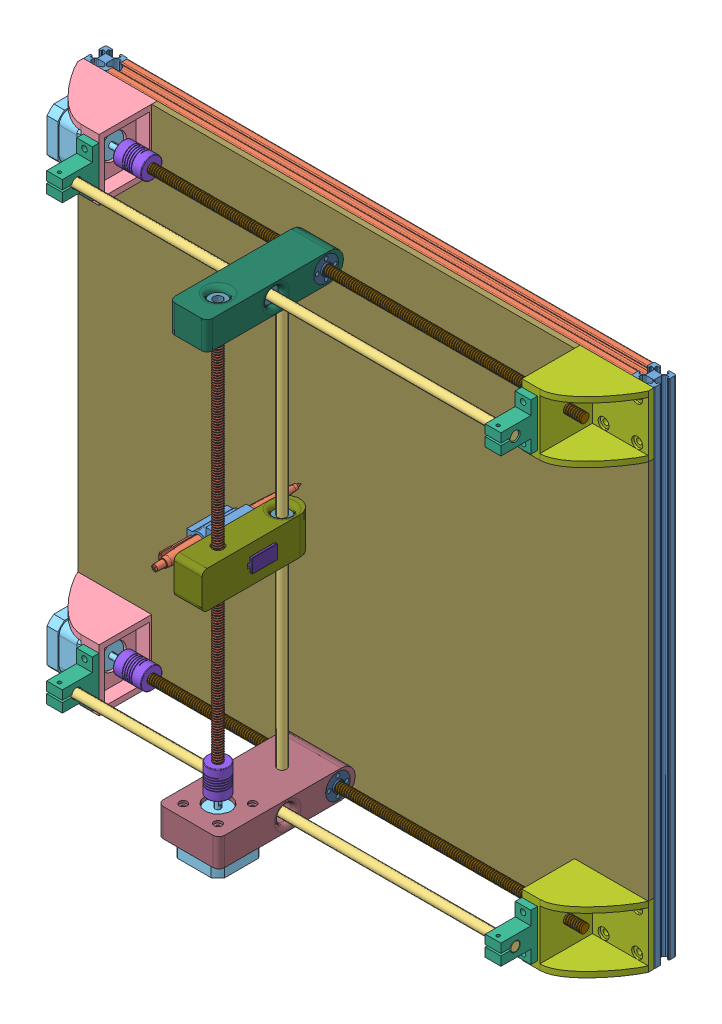
SolidWorks assembly Assem1, configuration Default. Lengths in mm.
Overall size (510 601.35 155.57).
39 component instances, 20 part files, 97 mates.
Components (placement in the parent):
- Profile20X20X450-1: Profile20X20X450 [Default] at (128.2703 40.515 345.5202) size (20 450 20)
- Profile20X20X470-1: Profile20X20X470 [Default] at (118.2703 50.515 345.5202) x (0 1 0) z (0 0 1) size (20 470 20)
- Profile20X20X450-2: Profile20X20X450 [Default] at (-361.7297 40.515 345.5202) size (20 450 20)
- Profile20X20X470-2: Profile20X20X470 [Default] at (118.2703 480.515 345.5202) x (0 0 -1) z (0 1 0) size (20 470 20)
- Rod405-1: Rod405 [Default] at (85.2703 463.015 427.5202) x (0 -0.389511 0.921022) z (0 -0.921022 -0.389511) size (8 405 8)
- Y Motor Mount-1: Y Motor Mount [Default] at (-346.7297 463.015 355.5202) x (0 -1 0) z (0 0 1) size (55 66 52)
- NEMA17-1: NEMA17 [Default] at (-321.7297 463.015 382.5202) x (-1 0 0) z (0 0 1) size (54.3 42.3 42.3)
- Rod Support-1: Rod Support [Default] at (-319.7297 463.015 410.5202) x (0 1 0) z (1 0 0) size (42 32.8 14)
- Y Mount-1: Y Mount [Default] at (113.2703 463.015 355.5202) x (0 1 0) z (0 0 1) size (55 66 52)
- Rod Support-2: Rod Support [Default] at (72.2703 463.015 410.5202) x (0 1 0) z (1 0 0) size (42 32.8 14)
- Coupling-1: Coupling [Default] at (-308.7297 463.015 382.5202) x (0 -0.956542 -0.291595) z (0 -0.291595 0.956542) size (19.01 25 19.98)
- Lead Screw 405-1: Lead Screw 405 [Default] at (-301.7297 463.015 382.5202) x (0 0.596667 -0.802489) z (0 -0.802489 -0.596667) size (8.47 411.14 9.26)
- NEMA17-2: NEMA17 [Default] at (-321.7297 68.015 382.5202) x (-1 0 0) z (0 0 1) size (54.3 42.3 42.3)
- Y Motor Mount-2: Y Motor Mount [Default] at (-346.7297 68.015 355.5202) x (0 -1 0) z (0 0 1) size (55 66 52)
- Rod405-2: Rod405 [Default] at (86.2703 68.015 427.5202) x (0 1 0) z (0 0 1) size (8 405 8)
- Rod Support-3: Rod Support [Default] at (-305.7297 68.015 410.5202) x (0 -1 0) z (-1 0 0) size (42 32.8 14)
- Y Mount-2: Y Mount [Default] at (113.2703 68.015 355.5202) x (0 1 0) z (0 0 1) size (55 66 52)
- Rod Support-4: Rod Support [Default] at (72.2703 68.015 410.5202) x (0 1 0) z (1 0 0) size (42 32.8 14)
- Coupling-2: Coupling [Default] at (-308.7297 68.015 382.5202) x (0 -0.905924 -0.42344) z (0 -0.42344 0.905924) size (19.01 25 19.98)
- Lead Screw 405-2: Lead Screw 405 [Default] at (-301.7297 68.015 382.5202) x (0 0.781118 -0.624384) z (0 -0.624384 -0.781118) size (8.47 411.14 9.26)
- Lead Screw Nut-1: Lead Screw Nut [Default] at (-117.1715 68.015 382.5202) x (0 -1 0) z (0 0 -1) size (22 16.61 22)
- Lead Screw Nut-2: Lead Screw Nut [Default] at (-127.6715 463.015 382.5202) x (0 -1 0) z (0 0 -1) size (22 16.61 22)
- Lead Screw 355-2: Lead Screw 355 [Default] at (-144.6715 95.515 462.2702) x (0.982445 0 -0.186554) z (0.186554 0 0.982445) size (8.47 360.68 9.26)
- Bottom Board-1: Bottom Board [Default] at (-116.7297 265.515 355.5202) x (0 1 0) z (1 0 0) size (601.35 5 510)
- X Motor Mount-1: X Motor Mount [Default] at (-144.6715 80.515 428.0202) x (1 0 0) z (0 -1 0) size (55 122 25)
- Rod Bearing-1: Rod Bearing [Default] at (-156.6715 68.015 427.5202) x (0 -1 0) z (0 0 1) size (15 24 15)
- NEMA17-3: NEMA17 [Default] at (-144.6715 75.515 462.2702) x (0 -1 0) z (0 0 1) size (54.3 42.3 42.3)
- Coupling-3: Coupling [Default] at (-144.6715 88.515 462.2702) x (-0.731937 0 -0.681372) z (0.681372 0 -0.731937) size (19.01 25 19.98)
- Rod405-3: Rod405 [Default] at (-144.6715 62.515 405.0202) x (0.332064 0 -0.943257) z (0.943257 0 0.332064) size (8 405 8)
- X Mount-1: X Mount [Default] at (-144.6715 450.515 428.0202) x (-1 0 0) z (0 1 0) size (34 122 25)
- Rod Bearing-2: Rod Bearing [Default] at (-157.1715 463.015 427.5202) x (0 -1 0) z (0 0 1) size (15 24 15)
- Rod Bearing-3: Rod Bearing [Default] at (-144.6715 471.015 462.2702) x (-1 0 0) z (0 0 1) size (15 24 15)
- Laser Mount-1: Laser Mount [Default] at (-157.1715 263.4641 439.0202) x (0 1 0) z (1 0 0) size (33 100 27)
- Rod Bearing-4: Rod Bearing [Default] at (-144.6715 275.4641 405.0202) x (0.034876 0 0.999392) z (0.999392 0 -0.034876) size (15 24 15)
- Lead Screw Nut-3: Lead Screw Nut [Default] at (-144.6715 246.9641 462.2702) x (-1 0 0) z (0 0 -1) size (22 16.61 22)
- SG90-1: SG90 [По умолчанию] at (-130.1715 263.4641 434.7702) x (0 0 1) z (0 -1 0) size (32.5 30.1 12.68)
- Servo Arm-1: Servo Arm [Default] at (-161.9715 263.4641 429.5202) x (0 -0.999945 -0.010487) z (0 -0.010487 0.999945) size (19.64 3.7 7)
- Laser holder-1: Laser holder [Default] at (-157.1715 263.2641 433.5202) x (0 -1 0) z (0 0 -1) size (30 26.04 36)
- Pen-1: Pen [Default] at (-172.4961 263.2641 364.5065) x (0.849805 -0.527097 0) z (-0.527097 -0.849805 0) size (12.47 130.57 10.33)
Mates (geometry in assembly coordinates):
- Coincident1: coincident aligned: plane of Profile20X20X450-1 through (119.7703 490.515 355.5202) normal (0 0 1); plane of Profile20X20X450-2 through (-370.2297 490.515 355.5202) normal (0 0 1)
- Coincident2: coincident aligned: plane of Profile20X20X450-1 through (122.8703 40.515 348.2686) normal (0 -1 0); plane of Profile20X20X450-2 through (-367.1297 40.515 348.2686) normal (0 -1 0)
- Coincident3: coincident aligned: plane of Profile20X20X450-1 through (136.7703 490.515 355.5202) normal (0 0 1); plane of Profile20X20X470-1 through (-351.7297 59.015 355.5202) normal (0 0 1)
- Coincident4: coincident anti-aligned: plane of Profile20X20X450-1 through (118.2703 490.515 354.0202) normal (-1 0 0); plane of Profile20X20X470-1 through (118.2703 45.115 348.2686) normal (1 0 0)
- Coincident5: coincident aligned: plane of Profile20X20X450-1 through (122.8703 40.515 348.2686) normal (0 -1 0); plane of Profile20X20X470-1 through (-351.7297 40.515 354.0202) normal (0 -1 0)
- Coincident6: coincident anti-aligned: plane of Profile20X20X470-1 through (-351.7297 45.115 348.2686) normal (-1 0 0); plane of Profile20X20X450-2 through (-351.7297 490.515 349.9202) normal (1 0 0)
- Coincident7: coincident aligned: plane of Profile20X20X450-1 through (119.7703 490.515 355.5202) normal (0 0 1); plane of Profile20X20X470-2 through (-351.7297 489.015 355.5202) normal (0 0 1)
- Coincident8: coincident anti-aligned: plane of Profile20X20X450-1 through (118.2703 490.515 337.0202) normal (-1 0 0); plane of Profile20X20X470-2 through (118.2703 483.2634 350.9202) normal (1 0 0)
- Coincident9: coincident aligned: plane of Profile20X20X450-1 through (122.8703 490.515 348.2686) normal (0 1 0); plane of Profile20X20X470-2 through (-351.7297 490.515 337.0202) normal (0 1 0)
- Coincident10: coincident anti-aligned: plane of Profile20X20X470-2 through (-351.7297 489.015 355.5202) normal (0 0 1); plane of Y Motor Mount-1 through (-346.7297 463.015 355.5202) normal (0 0 -1)
- Coincident11: coincident aligned: plane of Profile20X20X450-2 through (-367.1297 490.515 348.2686) normal (0 1 0); plane of Y Motor Mount-1 through (-321.7297 490.515 360.5202) normal (0 1 0)
- Coincident12: coincident aligned: plane of Profile20X20X450-2 through (-371.7297 490.515 354.0202) normal (-1 0 0); plane of Y Motor Mount-1 through (-371.7297 490.515 360.5202) normal (-1 0 0)
- Concentric1: concentric aligned: cylinder of Y Motor Mount-1 through (-305.7297 463.015 382.5202) axis (-1 0 0) radius 11.5; cylinder of NEMA17-1 through (-321.2297 463.015 382.5202) axis (-1 0 0) radius 11
- Coincident13: coincident anti-aligned: plane of Y Motor Mount-1 through (-321.7297 463.015 355.5202) normal (-1 0 0); plane of NEMA17-1 through (-321.7297 463.015 382.5202) normal (1 0 0)
- Parallel1: parallel aligned: plane of Y Motor Mount-1 through (-346.7297 463.015 360.5202) normal (0 0 1); plane of NEMA17-1 through (-325.5547 463.015 403.6702) normal (0 0 1)
- Concentric2: concentric aligned: cylinder of Y Motor Mount-1 through (-312.7297 479.015 402.5202) axis (0 0 1) radius 2.5; cylinder of Rod Support-1 through (-312.7297 479.015 407.5192) axis (0 0 1) radius 2.5
- Coincident15: coincident anti-aligned: plane of Y Motor Mount-1 through (-305.7297 490.515 407.5202) normal (0 0 1); plane of Rod Support-1 through (-305.7297 442.015 407.5202) normal (0 0 -1)
- Coincident16: coincident aligned: plane of Y Motor Mount-1 through (-305.7297 463.015 355.5202) normal (1 0 0); plane of Rod Support-1 through (-305.7297 463.015 427.5202) normal (1 0 0)
- Concentric5: concentric anti-aligned: cylinder of Rod405-1 through (-319.7297 463.015 427.5202) axis (1 0 0) radius 4; cylinder of Rod Support-1 through (-305.7297 463.015 427.5202) axis (-1 0 0) radius 4.5
- Coincident17: coincident aligned: plane of Rod405-1 through (-319.7297 463.015 427.5202) normal (-1 0 0); plane of Rod Support-1 through (-319.7297 463.015 427.5202) normal (-1 0 0)
- Coincident18: coincident aligned: plane of Profile20X20X450-1 through (138.2703 490.515 349.9202) normal (1 0 0); plane of Y Mount-1 through (138.2703 435.515 360.5202) normal (1 0 0)
- Coincident19: coincident anti-aligned: plane of Profile20X20X450-1 through (119.7703 490.515 355.5202) normal (0 0 1); plane of Y Mount-1 through (113.2703 463.015 355.5202) normal (0 0 -1)
- Coincident20: coincident aligned: plane of Profile20X20X450-1 through (122.8703 490.515 348.2686) normal (0 1 0); plane of Y Mount-1 through (88.2703 490.515 360.5202) normal (0 1 0)
- Concentric6: concentric anti-aligned: cylinder of Rod405-1 through (-319.7297 463.015 427.5202) axis (1 0 0) radius 4; cylinder of Rod Support-2 through (86.2703 463.015 427.5202) axis (-1 0 0) radius 4.5
- Concentric8: concentric aligned: cylinder of Y Mount-1 through (79.2703 447.015 402.5202) axis (0 0 1) radius 2.5; cylinder of Rod Support-2 through (79.2703 447.015 407.5192) axis (0 0 1) radius 2.5
- Concentric9: concentric aligned: cylinder of NEMA17-1 through (-317.4797 463.015 382.5202) axis (-1 0 0) radius 2.5; cylinder of Coupling-1 through (-283.7297 463.015 382.5202) axis (-1 0 0) radius 2.5
- Coincident21: coincident aligned: plane of NEMA17-1 through (-301.7297 462.015 382.5202) normal (1 0 0); plane of Coupling-1 through (-301.7297 463.015 382.5202) normal (1 0 0)
- Concentric10: concentric anti-aligned: cylinder of Coupling-1 through (-301.7297 463.015 382.5202) axis (1 0 0) radius 4; cylinder of Lead Screw 405-1 through (103.2703 463.015 382.5202) axis (-1 0 0) radius 4
- Coincident22: coincident anti-aligned: plane of Coupling-1 through (-301.7297 463.015 382.5202) normal (1 0 0); plane of Lead Screw 405-1 through (-301.7297 463.015 382.5202) normal (-1 0 0)
- Coincident23: coincident aligned: plane of Profile20X20X450-2 through (-367.1297 40.515 348.2686) normal (0 -1 0); plane of Y Motor Mount-2 through (-321.7297 40.515 360.5202) normal (0 -1 0)
- Coincident24: coincident anti-aligned: plane of Profile20X20X450-2 through (-353.2297 490.515 355.5202) normal (0 0 1); plane of Y Motor Mount-2 through (-346.7297 68.015 355.5202) normal (0 0 -1)
- Coincident25: coincident aligned: plane of Profile20X20X450-2 through (-371.7297 490.515 337.0202) normal (-1 0 0); plane of Y Motor Mount-2 through (-371.7297 95.515 360.5202) normal (-1 0 0)
- Concentric12: concentric aligned: cylinder of NEMA17-2 through (-317.4797 68.015 382.5202) axis (-1 0 0) radius 2.5; cylinder of Y Motor Mount-2 through (-305.7297 68.015 382.5202) axis (-1 0 0) radius 11.5
- Coincident26: coincident anti-aligned: plane of NEMA17-2 through (-321.7297 68.015 382.5202) normal (1 0 0); plane of Y Motor Mount-2 through (-321.7297 68.015 355.5202) normal (-1 0 0)
- Parallel4: parallel aligned: plane of NEMA17-2 through (-325.5547 68.015 403.6702) normal (0 0 1); plane of Y Motor Mount-2 through (-305.7297 95.515 407.5202) normal (0 0 1)
- Concentric13: concentric aligned: cylinder of Y Motor Mount-2 through (-312.7297 84.015 402.5202) axis (0 0 1) radius 2.5; cylinder of Rod Support-3 through (-312.7297 84.015 407.5192) axis (0 0 1) radius 2.5
- Coincident28: coincident anti-aligned: plane of Y Motor Mount-2 through (-305.7297 95.515 407.5202) normal (0 0 1); plane of Rod Support-3 through (-319.7297 89.015 407.5202) normal (0 0 -1)
- Concentric14: concentric aligned: cylinder of Y Motor Mount-2 through (-312.7297 52.015 402.5202) axis (0 0 1) radius 2.5; cylinder of Rod Support-3 through (-312.7297 52.015 407.5192) axis (0 0 1) radius 2.5
- Coincident29: coincident aligned: plane of Profile20X20X450-1 through (122.8703 40.515 348.2686) normal (0 -1 0); plane of Y Mount-2 through (88.2703 40.515 360.5202) normal (0 -1 0)
- Coincident30: coincident aligned: plane of Profile20X20X450-1 through (138.2703 490.515 349.9202) normal (1 0 0); plane of Y Mount-2 through (138.2703 40.515 360.5202) normal (1 0 0)
- Coincident31: coincident anti-aligned: plane of Profile20X20X450-1 through (119.7703 490.515 355.5202) normal (0 0 1); plane of Y Mount-2 through (113.2703 68.015 355.5202) normal (0 0 -1)
- Concentric15: concentric aligned: cylinder of Y Mount-2 through (79.2703 52.015 402.5202) axis (0 0 1) radius 2.5; cylinder of Rod Support-4 through (79.2703 52.015 407.5192) axis (0 0 1) radius 2.5
- Concentric16: concentric aligned: cylinder of Y Mount-2 through (79.2703 84.015 402.5202) axis (0 0 1) radius 2.5; cylinder of Rod Support-4 through (79.2703 84.015 407.5192) axis (0 0 1) radius 2.5
- Coincident32: coincident anti-aligned: plane of Y Mount-2 through (72.2703 40.515 407.5202) normal (0 0 1); plane of Rod Support-4 through (86.2703 47.015 407.5202) normal (0 0 -1)
- Concentric17: concentric aligned: cylinder of Rod405-2 through (-318.7297 68.015 427.5202) axis (1 0 0) radius 4; cylinder of Rod Support-3 through (-319.7297 68.015 427.5202) axis (1 0 0) radius 4.5
- Coincident33: coincident aligned: plane of Rod405-2 through (86.2703 68.015 427.5202) normal (1 0 0); plane of Rod Support-4 through (86.2703 68.015 427.5202) normal (1 0 0)
- Concentric19: concentric aligned: cylinder of NEMA17-2 through (-317.4797 68.015 382.5202) axis (-1 0 0) radius 2.5; cylinder of Coupling-2 through (-283.7297 68.015 382.5202) axis (-1 0 0) radius 2.5
- Coincident34: coincident aligned: plane of NEMA17-2 through (-301.7297 67.015 382.5202) normal (1 0 0); plane of Coupling-2 through (-301.7297 68.015 382.5202) normal (1 0 0)
- Concentric20: concentric anti-aligned: cylinder of Coupling-2 through (-301.7297 68.015 382.5202) axis (1 0 0) radius 4; cylinder of Lead Screw 405-2 through (103.2703 68.015 382.5202) axis (-1 0 0) radius 4
- Coincident35: coincident anti-aligned: plane of Coupling-2 through (-301.7297 68.015 382.5202) normal (1 0 0); plane of Lead Screw 405-2 through (-301.7297 68.015 382.5202) normal (-1 0 0)
- Concentric21: concentric anti-aligned: cylinder of Lead Screw 405-2 through (103.2703 68.015 382.5202) axis (-1 0 0) radius 4; cylinder of Lead Screw Nut-1 through (-130.6715 68.015 382.5202) axis (1 0 0) radius 5
- Concentric22: concentric anti-aligned: cylinder of Lead Screw 405-1 through (103.2703 463.015 382.5202) axis (-1 0 0) radius 4; cylinder of Lead Screw Nut-2 through (-141.1715 463.015 382.5202) axis (1 0 0) radius 5
- Coincident36: coincident anti-aligned: plane of Profile20X20X450-1 through (119.7703 490.515 355.5202) normal (0 0 1); plane of Bottom Board-1 through (-116.7297 265.515 355.5202) normal (0 0 -1)
- Coincident37: coincident aligned: plane of Profile20X20X450-1 through (138.2703 490.515 349.9202) normal (1 0 0); plane of Bottom Board-1 through (138.2703 95.515 360.5202) normal (1 0 0)
- Coincident38: coincident aligned: plane of Profile20X20X470-1 through (-351.7297 40.515 354.0202) normal (0 -1 0); plane of Bottom Board-1 through (-305.7297 40.515 360.5202) normal (0 -1 0)
- Concentric24: concentric aligned: cylinder of Rod405-2 through (-318.7297 68.015 427.5202) axis (1 0 0) radius 4; cylinder of X Motor Mount-1 through (-172.1715 68.015 427.5202) axis (1 0 0) radius 7.5
- Concentric25: concentric anti-aligned: cylinder of Rod405-2 through (-318.7297 68.015 427.5202) axis (1 0 0) radius 4; cylinder of Rod Bearing-1 through (-132.6715 68.015 427.5202) axis (-1 0 0) radius 7.5
- Distance1: distance = 15.5 mm aligned: plane of X Motor Mount-1 through (-172.1715 55.515 489.0202) normal (-1 0 0); plane of Rod Bearing-1 through (-156.6715 68.015 427.5202) normal (-1 0 0)
- Parallel5: parallel aligned: plane of Profile20X20X470-1 through (-351.7297 40.515 354.0202) normal (0 -1 0); plane of X Motor Mount-1 through (-144.6715 55.515 428.0202) normal (0 -1 0)
- Concentric26: concentric aligned: cylinder of Lead Screw Nut-1 through (-120.6715 68.015 374.5202) axis (1 0 0) radius 1.75; cylinder of X Motor Mount-1 through (-130.6715 68.015 374.5202) axis (1 0 0) radius 1.4
- Coincident41: coincident anti-aligned: plane of Lead Screw Nut-1 through (-120.6715 68.015 382.5202) normal (-1 0 0); plane of X Motor Mount-1 through (-120.6715 68.015 382.5202) normal (1 0 0)
- Concentric27: concentric anti-aligned: cylinder of X Motor Mount-1 through (-144.6715 55.515 462.2702) axis (0 1 0) radius 11.5; cylinder of NEMA17-3 through (-144.6715 79.765 462.2702) axis (0 -1 0) radius 2.5
- Concentric28: concentric anti-aligned: cylinder of X Motor Mount-1 through (-129.1715 55.515 477.7702) axis (0 1 0) radius 1.5; cone of NEMA17-3 through (-129.1715 75.3797 477.7702) axis (0 -1 0)
- Coincident42: coincident anti-aligned: plane of X Motor Mount-1 through (-144.6715 75.515 428.0202) normal (0 -1 0); plane of NEMA17-3 through (-144.6715 75.515 462.2702) normal (0 1 0)
- Concentric30: concentric aligned: cylinder of NEMA17-3 through (-144.6715 79.765 462.2702) axis (0 -1 0) radius 2.5; cylinder of Coupling-3 through (-144.6715 113.515 462.2702) axis (0 -1 0) radius 2.5
- Coincident43: coincident aligned: plane of NEMA17-3 through (-143.6715 95.515 462.2702) normal (0 1 0); plane of Coupling-3 through (-144.6715 95.515 462.2702) normal (0 1 0)
- Concentric31: concentric anti-aligned: cylinder of Lead Screw 355-2 through (-144.6715 450.515 462.2702) axis (0 -1 0) radius 4; cylinder of Coupling-3 through (-144.6715 95.515 462.2702) axis (0 1 0) radius 4
- Coincident44: coincident anti-aligned: plane of Lead Screw 355-2 through (-144.6715 95.515 462.2702) normal (0 -1 0); plane of Coupling-3 through (-144.6715 95.515 462.2702) normal (0 1 0)
- Concentric33: concentric anti-aligned: cylinder of X Motor Mount-1 through (-144.6715 62.515 405.0202) axis (0 1 0) radius 4.1; cylinder of Rod405-3 through (-144.6715 467.515 405.0202) axis (0 -1 0) radius 4
- Coincident46: coincident anti-aligned: plane of X Motor Mount-1 through (-144.6715 62.515 405.0202) normal (0 1 0); plane of Rod405-3 through (-144.6715 62.515 405.0202) normal (0 -1 0)
- Concentric37: concentric anti-aligned: cylinder of Rod405-1 through (-319.7297 463.015 427.5202) axis (1 0 0) radius 4; cylinder of X Mount-1 through (-127.6715 463.015 427.5202) axis (-1 0 0) radius 7.5
- Concentric38: concentric aligned: cylinder of Lead Screw 405-1 through (103.2703 463.015 382.5202) axis (-1 0 0) radius 4; cylinder of X Mount-1 through (-127.6715 463.015 382.5202) axis (-1 0 0) radius 5.1
- Concentric39: concentric aligned: cylinder of Rod405-3 through (-144.6715 467.515 405.0202) axis (0 -1 0) radius 4; cylinder of X Mount-1 through (-144.6715 468.515 405.0202) axis (0 -1 0) radius 4.1
- Concentric40: concentric anti-aligned: cylinder of Rod405-1 through (-319.7297 463.015 427.5202) axis (1 0 0) radius 4; cylinder of Rod Bearing-2 through (-133.1715 463.015 427.5202) axis (-1 0 0) radius 7.5
- Distance3: distance = 4.5 mm aligned: plane of X Mount-1 through (-161.6715 475.515 489.0202) normal (-1 0 0); plane of Rod Bearing-2 through (-157.1715 463.015 427.5202) normal (-1 0 0)
- Concentric41: concentric aligned: cylinder of Lead Screw Nut-2 through (-131.1715 463.015 390.5202) axis (1 0 0) radius 1.75; cylinder of X Mount-1 through (-141.1715 463.015 390.5202) axis (1 0 0) radius 1.4
- Coincident49: coincident anti-aligned: plane of Lead Screw Nut-2 through (-131.1715 463.015 382.5202) normal (-1 0 0); plane of X Mount-1 through (-131.1715 463.015 382.5202) normal (1 0 0)
- Concentric42: concentric anti-aligned: cylinder of X Mount-1 through (-144.6715 475.515 462.2702) axis (0 -1 0) radius 7.5; cylinder of Rod Bearing-3 through (-144.6715 447.015 462.2702) axis (0 1 0) radius 7.5
- Tangent1: tangent aligned: plane of Rod Bearing-3 through (-144.6715 471.015 462.2702) normal (0 1 0); circle of X Mount-1
- Concentric44: concentric aligned: cylinder of Rod405-3 through (-144.6715 467.515 405.0202) axis (0 -1 0) radius 4; cylinder of Laser Mount-1 through (-144.6715 279.9641 405.0202) axis (0 -1 0) radius 7.5
- Concentric45: concentric aligned: cylinder of Lead Screw 355-2 through (-144.6715 450.515 462.2702) axis (0 -1 0) radius 4; cylinder of Laser Mount-1 through (-144.6715 279.9641 462.2702) axis (0 -1 0) radius 5.1
- Concentric46: concentric aligned: cylinder of Laser Mount-1 through (-144.6715 279.9641 462.2702) axis (0 -1 0) radius 5.1; cylinder of Lead Screw Nut-3 through (-144.6715 260.4641 462.2702) axis (0 -1 0) radius 5
- Concentric47: concentric aligned: cylinder of Laser Mount-1 through (-144.6715 260.4641 470.2702) axis (0 -1 0) radius 1.4; cylinder of Lead Screw Nut-3 through (-144.6715 250.4641 470.2702) axis (0 -1 0) radius 1.75
- Coincident51: coincident anti-aligned: plane of Laser Mount-1 through (-144.6715 250.4641 462.2702) normal (0 -1 0); plane of Lead Screw Nut-3 through (-144.6715 250.4641 462.2702) normal (0 1 0)
- Concentric48: concentric anti-aligned: cylinder of Rod405-3 through (-144.6715 467.515 405.0202) axis (0 -1 0) radius 4; cylinder of Rod Bearing-4 through (-144.6715 251.4641 405.0202) axis (0 1 0) radius 7.5
- Coincident52: coincident aligned: circle of Laser Mount-1; plane of Rod Bearing-4 through (-144.6715 251.4641 405.0202) normal (0 -1 0)
- Concentric49: concentric anti-aligned: cylinder of Laser Mount-1 through (-139.1715 263.4641 448.5202) axis (-1 0 0) radius 0.75; cylinder of SG90-1 through (-148.6715 263.4641 448.5202) axis (1 0 0) radius 1
- Concentric50: concentric anti-aligned: cylinder of Laser Mount-1 through (-139.1715 263.4641 421.0202) axis (-1 0 0) radius 0.75; cylinder of SG90-1 through (-148.6715 263.4641 421.0202) axis (1 0 0) radius 1
- Coincident53: coincident anti-aligned: plane of Laser Mount-1 through (-146.1715 263.4641 439.0202) normal (-1 0 0); plane of SG90-1 through (-146.1715 263.4641 434.7702) normal (1 0 0)
- Concentric52: concentric anti-aligned: cylinder of SG90-1 through (-160.2715 263.4641 429.5202) axis (1 0 0) radius 2.5; cylinder of Servo Arm-1 through (-158.2715 263.4641 429.5202) axis (-1 0 0) radius 3.5
- Coincident55: coincident anti-aligned: plane of SG90-1 through (-160.2715 263.4641 429.5202) normal (-1 0 0); plane of Servo Arm-1 through (-160.2715 263.4641 429.5202) normal (1 0 0)
- Coincident56: coincident anti-aligned: plane of Laser Mount-1 through (-157.1715 263.4641 439.0202) normal (-1 0 0); plane of Laser holder-1 through (-157.1715 263.2641 433.5202) normal (1 0 0)
- Parallel6: parallel aligned: plane of Laser Mount-1 through (-132.1715 246.9641 489.0202) normal (0 0 1); plane of Laser holder-1 through (-166.1715 278.2641 451.5202) normal (0 0 1)
- Coincident61: coincident aligned: line of Laser Mount-1 through (-157.1715 253.4641 456.0202) axis (0 0 -1); line of Laser holder-1 through (-157.1715 253.4641 451.5202) axis (0 0 -1)
- Coincident63: coincident anti-aligned: plane of Laser Mount-1 through (-157.1715 263.4641 415.5202) normal (0 0 1); plane of Laser holder-1 through (-166.1715 278.2641 415.5202) normal (0 0 -1)
- Concentric53: concentric anti-aligned: cylinder of Laser holder-1 through (-172.4961 263.2641 415.5202) axis (0 0 1) radius 6; cylinder of Pen-1 through (-172.4961 263.2641 365.1008) axis (0 0 -1) radius 2.88
- Tangent2: tangent anti-aligned: plane of Bottom Board-1 through (-116.7297 265.515 360.5202) normal (0 0 1); sphere of Pen-1
